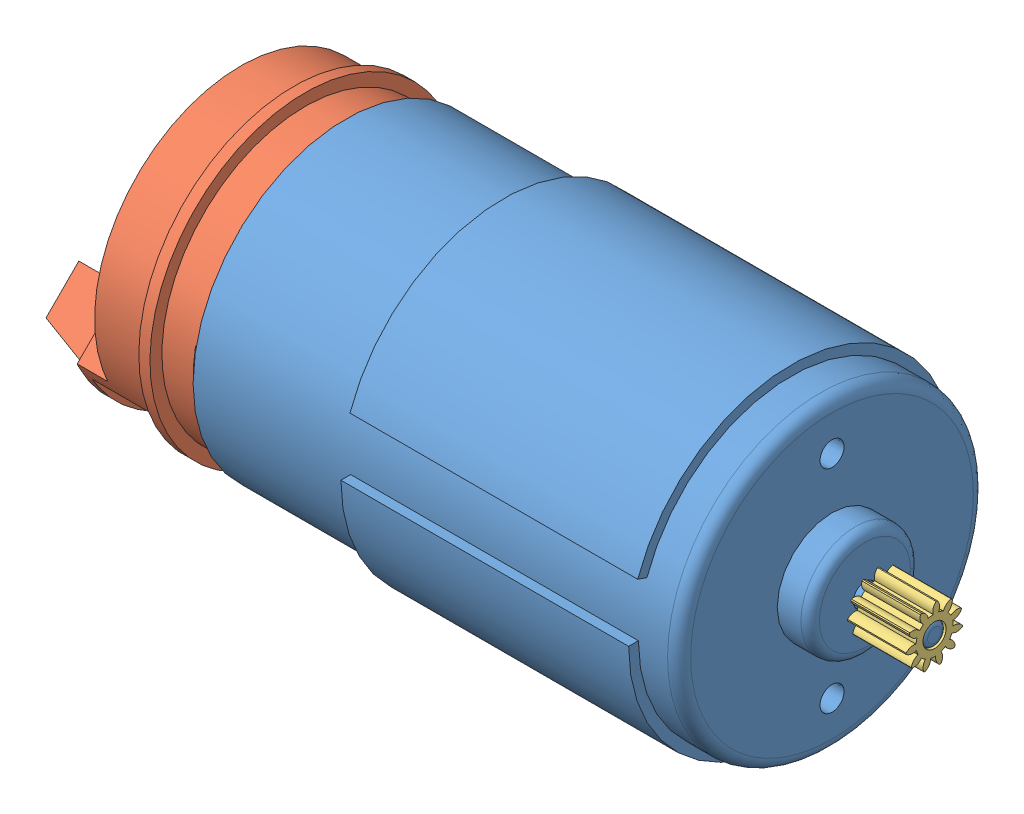
SolidWorks assembly am-3109 RS775-125 with Encoder for PG27 Gearbox REV2, configuration Default. Lengths in mm.
Overall size (106.44 60.02 60.02).
3 component instances, 3 part files, 0 mates.
Components (placement in the parent):
- RS775 with Backshaft-1: RS775 with Backshaft [Default] at (-72.3148 29.6356 1.4379) size (98.18 44.5 44.5)
- Hall Effect Encoder for PG Gearboxes-1: Hall Effect Encoder for PG Gearboxes [Default] at (-70.4098 29.6356 1.4379) x (0 0.707107 0.707107) z (0 -0.707107 0.707107) size (42.44 27.83 42.44)
- 11T 0.6mod 20PA 8mm FW gear-1: 11T 0.6mod 20PA 8mm FW gear [Default] at (0.2074 29.6356 1.4379) x (1 0 0) z (0 -0.976252 0.216639) size (8 7.67 7.74)
